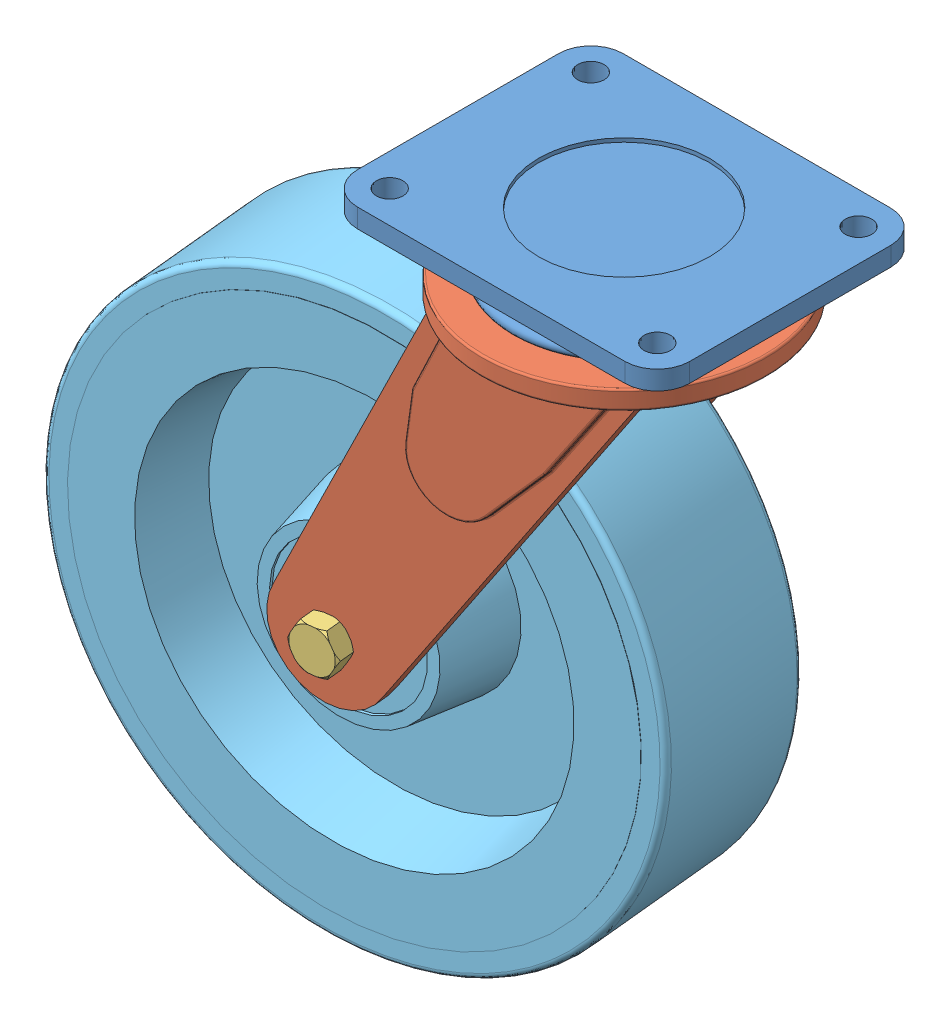
SolidWorks assembly castor wheel, configuration Default. Lengths in mm.
Overall size (367.65 390.18 244.98).
6 component instances, 5 part files, 11 mates.
Components (placement in the parent):
- mounting plate-2: mounting plate [Default] at (40.8741 108.2166 147.6418) size (175 55 140)
- 3.horn-1: 3.horn [Default] at (40.8741 78.2166 147.6418) x (0.994971 0 -0.100159) z (0.100159 0 0.994971) size (202 210 150)
- 4.Bolt-1: 4.Bolt [Default] at (-50.1294 -91.7834 212.0806) x (0.870609 -0.484106 -0.08764) z (-0.481671 -0.875009 0.048487) size (22 136 25.4)
- nut-1: nut [Default] at (40.8741 68.2166 147.6418) size (22 10 25.4)
- 5.rim-1: 5.rim [Default] at (-55.6382 -91.7834 157.3572) x (0.968895 0.227441 -0.097534) z (0.100159 0 0.994971) size (300 300 87)
- nut-2: nut [Default] at (-61.1469 -91.7834 102.6337) x (0.387713 0.920954 -0.039029) z (-0.916323 0.389672 0.092241) size (22 10 25.4)
Mates (geometry in assembly coordinates):
- Coincident2: coincident aligned: cylinder of mounting plate-2 through (40.8741 63.2166 147.6418) axis (0 1 0) radius 7.5; circle of 3.horn-1
- Coincident3: coincident anti-aligned: plane of mounting plate-2 through (40.8741 88.2166 147.6418) normal (0 -1 0); plane of 3.horn-1 through (40.8741 88.2166 147.6418) normal (0 1 0)
- Concentric1: concentric aligned: cylinder of mounting plate-2 through (40.8741 63.2166 147.6418) axis (0 1 0) radius 7.5; cylinder of nut-1 through (40.8741 68.2166 147.6418) axis (0 1 0) radius 7.5
- Coincident4: coincident anti-aligned: plane of 3.horn-1 through (40.8741 78.2166 147.6418) normal (0 -1 0); plane of nut-1 through (40.8741 78.2166 147.6418) normal (0 1 0)
- Concentric2: concentric aligned: cylinder of 3.horn-1 through (-50.1294 -91.7834 212.0806) axis (-0.100159 0 -0.994971) radius 7.5; cylinder of 5.rim-1 through (-51.2813 -91.7834 200.6384) axis (-0.100159 0 -0.994971) radius 7.5
- Distance1: distance = 5 mm: plane of 5.rim-1 through (-59.8448 -91.7834 115.5684) normal (-0.100159 0 -0.994971); plane of 3.horn-1 through (-60.3456 -91.7834 110.5935) normal (0.100159 0 0.994971)
- Distance2: distance = 5 mm: plane of 5.rim-1 through (-51.4315 -91.7834 199.146) normal (0.100159 0 0.994971); plane of 3.horn-1 through (-50.9307 -91.7834 204.1208) normal (-0.100159 0 -0.994971)
- Concentric3: concentric anti-aligned: cylinder of 3.horn-1 through (-50.1294 -91.7834 212.0806) axis (-0.100159 0 -0.994971) radius 7.5; cylinder of 4.Bolt-1 through (-62.7494 -91.7834 86.7142) axis (0.100159 0 0.994971) radius 7.5
- Coincident10: coincident anti-aligned: plane of 3.horn-1 through (-50.1294 -91.7834 212.0806) normal (0.100159 0 0.994971); plane of 4.Bolt-1 through (-50.1294 -91.7834 212.0806) normal (-0.100159 0 -0.994971)
- Concentric4: concentric anti-aligned: cylinder of 4.Bolt-1 through (-62.7494 -91.7834 86.7142) axis (0.100159 0 0.994971) radius 7.5; cylinder of nut-2 through (-61.1469 -91.7834 102.6337) axis (-0.100159 0 -0.994971) radius 7.5
- Coincident11: coincident anti-aligned: plane of 3.horn-1 through (-61.1469 -91.7834 102.6337) normal (-0.100159 0 -0.994971); plane of nut-2 through (-61.1469 -91.7834 102.6337) normal (0.100159 0 0.994971)
